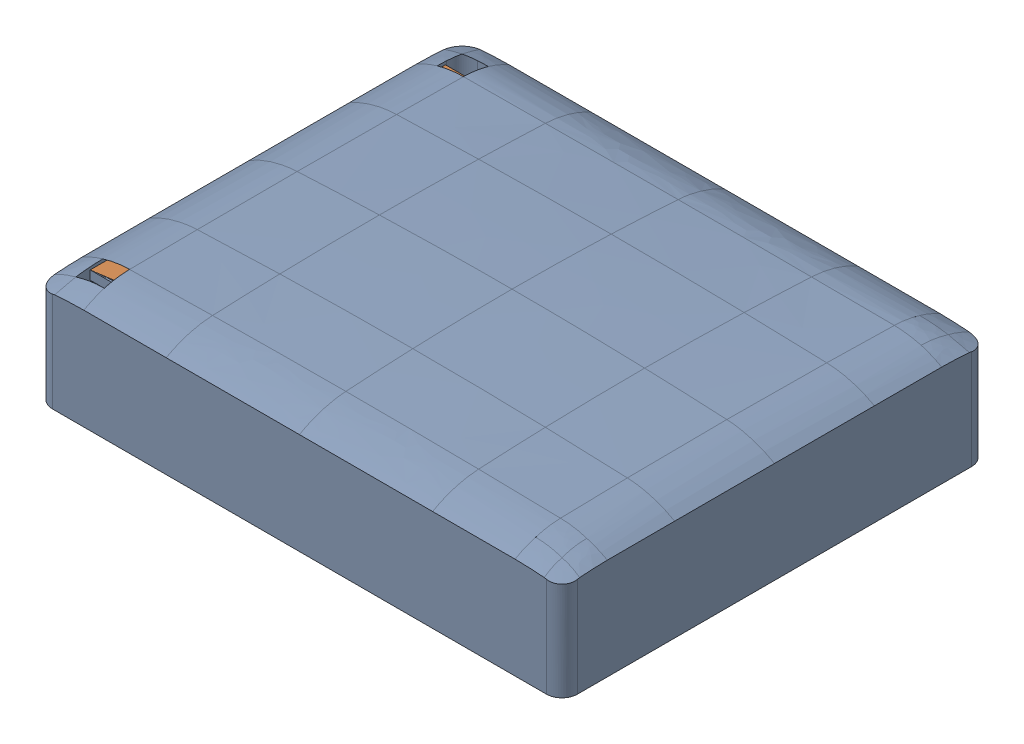
SolidWorks assembly 中间过程, configuration 默认. Lengths in mm.
Overall size (23.8 5.48 19.29).
2 component instances, 2 part files, 4 mates.
Components (placement in the parent):
- InsideSkin_conti-1: InsideSkin_conti [默认] at origin size (23.8 5.48 19.29)
- continuous-1: continuous [默认] at (-10.25 23.3 7.5) x (1 0 0) z (0 1 0) size (22 16 0.4)
Mates (geometry in assembly coordinates):
- 重合1: coordinate: point of InsideSkin_conti-1
- 宽度1: width aligned: plane of continuous-1 through (10.75 23.7 7.5) normal (1 0 0); plane of InsideSkin_conti-1 through (-11.25 23.3 -3.4851) normal (-1 0 0); plane of continuous-1 through (11.575 17.7531 -9.375) normal (1 0 0); plane of InsideSkin_conti-1 through (-12.075 17.7531 -9.375) normal (-1 0 0)
- 宽度2: width aligned: plane of InsideSkin_conti-1 through (-11.375 17.7531 9.075) normal (0 0 1); plane of continuous-1 through (-11.375 17.7531 -10.075) normal (0 0 -1); plane of InsideSkin_conti-1 through (-10.25 23.7 7.5) normal (0 0 1); plane of continuous-1 through (-11.25 23.3 -8.5) normal (0 0 -1)
- 距离1: distance = 4.3 mm aligned: plane of InsideSkin_conti-1 through (10.875 19 -9.375) normal (0 -1 0); plane of continuous-1 through (-10.25 23.3 7.5) normal (0 -1 0)
